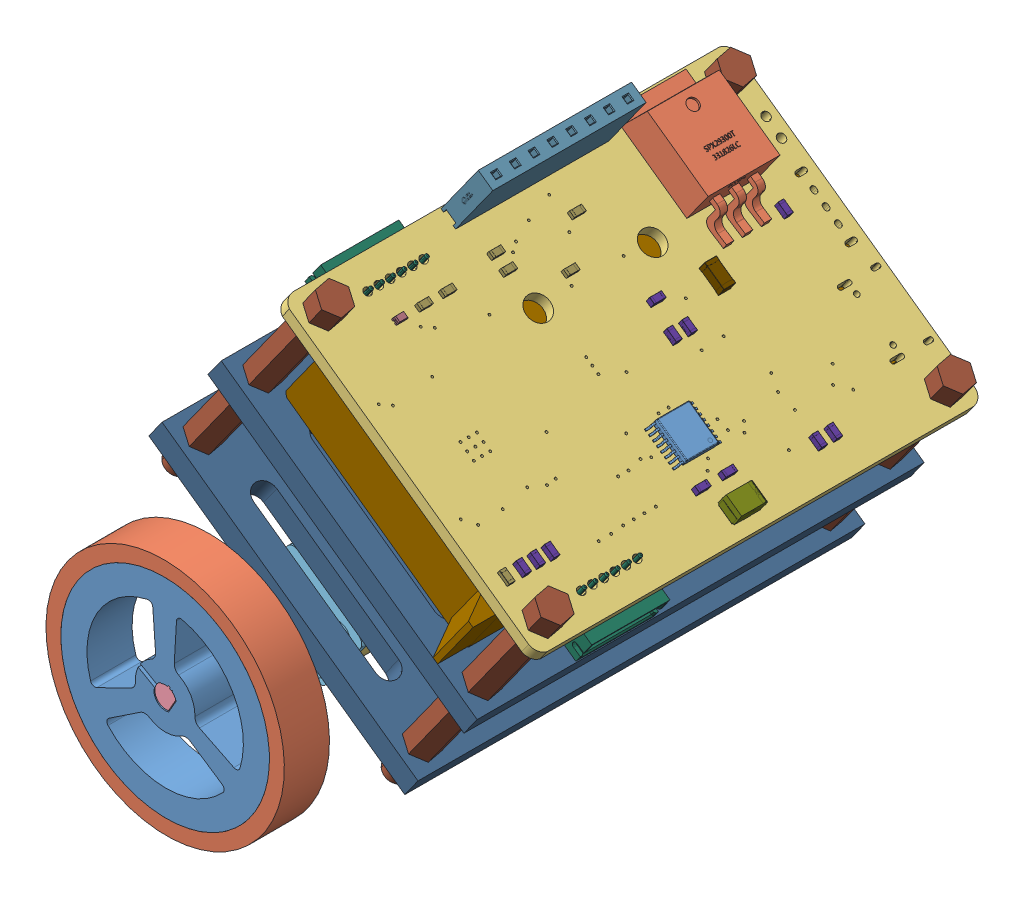
SolidWorks assembly 平衡车组装, configuration 默认. Lengths in mm.
Overall size (65.75 71.58 84.82).
118 component instances, 21 part files, 28 mates.
Components (placement in the parent):
- 轮胎-1: 轮胎 [默认] at (-1.4439 0.1126 20.4663) x (0.999988 -0.000017 0.004949) z (-0.004949 -0.006932 0.999964) size (28 28 6)
- 轮胎外胎-1: 轮胎外胎 [默认] at (-1.4439 0.1126 20.4663) x (0.781141 0.6243 0.008194) z (-0.004949 -0.006932 0.999964) size (32 32 6)
- n20 motor-2: n20 motor [轴长10mm] at (-1.1407 0.3816 3.3576) x (0.004949 0.006932 -0.999964) z (0.581014 0.813849 0.008518) size (36.2 12.14 10.87)
  - motor-1: motor [默认] at (-3.4114 0.0905 -5.0483) size (19.5 12 10)
  - n20_shaft-1: n20_shaft [10mm] at (-13.1114 0.0905 -0.0483) x (0 -0.096252 -0.995357) z (0 0.995357 -0.096252) size (3 12 3)
  - n20_gearbox-1: n20_gearbox [默认] at (-11.4114 0.0905 -0.0483) x (0 1 0) z (-1 0 0) size (12 10 9.7)
  - cross recessed countersunk head screws gb1-1: cross recessed countersunk head screws gb1 [GB_CROSS_SCREWS_TYPE4 M1.6X3-2  H type-N] at (-12.4614 -3.4095 2.4517) size (3 2.7 2.7)
  - cross recessed countersunk head screws gb1-2: cross recessed countersunk head screws gb1 [GB_CROSS_SCREWS_TYPE4 M1.6X3-2  H type-N] at (-12.4614 3.5905 -2.5483) x (1 0 0) z (0 0.116872 0.993147) size (3 2.7 2.7)
  - spur gear_gb-1: spur gear_gb [GB - Spur gear 0.25M 10T 20PA 2FW ---S10A75H50L1.0N] at (-8.4114 -2.9095 -2.5483) x (1 0 0) z (0 -0.845955 0.533254) size (2 2.87 3)
  - spur gear_gb-2: spur gear_gb [GB - Spur gear 0.25M 10T 20PA 2FW ---S10A75H50L1.0N] at (-4.4114 0.0905 -0.0483) x (-1 0 0) z (0 0.404067 -0.914729) size (2 2.87 3)
  - spur gear_gb-4: spur gear_gb [GB - Spur gear 0.25M 16T 20PA 2FW ---S16A75H50L1.0N] at (-6.4114 -2.9095 -2.5483) x (1 0 0) z (0 -0.712706 0.701463) size (2 4.44 4.44)
  - spur gear_gb-6: spur gear_gb [GB - Spur gear 0.25M 19T 20PA 2FW ---S19A75H50L1.0N] at (-9.9114 0.0905 -0.0483) x (1 0 0) z (0 0.321468 -0.94692) size (2 5.22 5.24)
  - spur gear_gb-8: spur gear_gb [GB - Spur gear 0.25M 11T 20PA 3FW ---S11A75H50L1.0N] at (-10.9114 3.0905 2.9517) x (1 0 0) z (0 -0.604063 0.796937) size (3 3.2 3.23)
  - spur gear_gb-10: spur gear_gb [GB - Spur gear 0.25M 19T 20PA 1FW ---S19A75H50L1.0N] at (-11.4114 0.0905 -0.0483) x (1 0 0) z (0 -0.330889 0.94367) size (1 5.22 5.24)
- 零件5-1: 零件5 [默认] at (-1.3018 0.3116 -8.2327) x (0.813878 -0.581035 0) z (0.004949 0.006932 -0.999964) size (11.6 18.42 6)
- 轮胎-2: 轮胎 [默认] at (-1.4735 0.071 -58.0123) x (0.999988 -0.000017 -0.004949) z (0.004949 0.006932 0.999964) size (28 28 6)
- 轮胎外胎-2: 轮胎外胎 [默认] at (-1.4735 0.071 -58.0123) x (0.781141 0.6243 -0.008194) z (0.004949 0.006932 0.999964) size (32 32 6)
- n20 motor-3: n20 motor [轴长10mm] at (-1.4302 -0.024 -34.8996) x (0.004949 0.006932 0.999964) z (-0.581014 -0.813849 0.008518) size (36.2 12.14 10.87)
  - motor-1: motor [默认] at (-3.4114 0.0905 -5.0483) size (19.5 12 10)
  - n20_shaft-1: n20_shaft [10mm] at (-13.1114 0.0905 -0.0483) x (0 -0.096252 -0.995357) z (0 0.995357 -0.096252) size (3 12 3)
  - n20_gearbox-1: n20_gearbox [默认] at (-11.4114 0.0905 -0.0483) x (0 1 0) z (-1 0 0) size (12 10 9.7)
  - cross recessed countersunk head screws gb1-1: cross recessed countersunk head screws gb1 [GB_CROSS_SCREWS_TYPE4 M1.6X3-2  H type-N] at (-12.4614 -3.4095 2.4517) size (3 2.7 2.7)
  - cross recessed countersunk head screws gb1-2: cross recessed countersunk head screws gb1 [GB_CROSS_SCREWS_TYPE4 M1.6X3-2  H type-N] at (-12.4614 3.5905 -2.5483) x (1 0 0) z (0 0.116872 0.993147) size (3 2.7 2.7)
  - spur gear_gb-1: spur gear_gb [GB - Spur gear 0.25M 10T 20PA 2FW ---S10A75H50L1.0N] at (-8.4114 -2.9095 -2.5483) x (1 0 0) z (0 -0.845955 0.533254) size (2 2.87 3)
  - spur gear_gb-2: spur gear_gb [GB - Spur gear 0.25M 10T 20PA 2FW ---S10A75H50L1.0N] at (-4.4114 0.0905 -0.0483) x (-1 0 0) z (0 0.404067 -0.914729) size (2 2.87 3)
  - spur gear_gb-4: spur gear_gb [GB - Spur gear 0.25M 16T 20PA 2FW ---S16A75H50L1.0N] at (-6.4114 -2.9095 -2.5483) x (1 0 0) z (0 -0.712706 0.701463) size (2 4.44 4.44)
  - spur gear_gb-6: spur gear_gb [GB - Spur gear 0.25M 19T 20PA 2FW ---S19A75H50L1.0N] at (-9.9114 0.0905 -0.0483) x (1 0 0) z (0 0.321468 -0.94692) size (2 5.22 5.24)
  - spur gear_gb-8: spur gear_gb [GB - Spur gear 0.25M 11T 20PA 3FW ---S11A75H50L1.0N] at (-10.9114 3.0905 2.9517) x (1 0 0) z (0 -0.604063 0.796937) size (3 3.2 3.23)
  - spur gear_gb-10: spur gear_gb [GB - Spur gear 0.25M 19T 20PA 1FW ---S19A75H50L1.0N] at (-11.4114 0.0905 -0.0483) x (1 0 0) z (0 -0.330889 0.94367) size (1 5.22 5.24)
- 零件5-2: 零件5 [默认] at (-1.3018 0.3116 -23.3136) x (-0.813878 0.581035 0) z (0.004949 0.006932 0.999964) size (11.6 18.42 6)
- 电池2S-1: 电池2S [默认] at (17.4767 27.9064 -17.9457) x (-0.004949 -0.006932 -0.999964) z (-0.581014 -0.813849 0.008518) size (62.44 30 12)
- 底板-1: 底板 [默认] at (1.0488 4.6094 -15.7714) x (-0.004949 -0.006932 -0.999964) z (0.581014 0.813849 -0.008518) size (60 42 3)
- 底板-2: 底板 [默认] at (8.9065 15.6161 -15.818) x (-0.004949 -0.006932 -0.999964) z (0.581014 0.813849 -0.008518) size (60 42 3)
- 铜柱-1: 铜柱 [默认] at (-11.9913 17.3229 -42.7274) x (0.665274 -0.468864 0.581014) z (-0.581014 -0.813849 0.008518) size (4.05 4.02 36)
- 铜柱-2: 铜柱 [默认] at (-11.7244 17.6968 11.2021) x (0.665274 -0.468864 0.581014) z (-0.581014 -0.813849 0.008518) size (4.05 4.02 36)
- 铜柱-3: 铜柱 [默认] at (17.308 -3.5948 -42.796) x (0.665274 -0.468864 0.581014) z (-0.581014 -0.813849 0.008518) size (4.05 4.02 36)
- 铜柱-4: 铜柱 [默认] at (17.5753 -3.2205 11.2021) x (0.665274 -0.468864 0.581014) z (-0.581014 -0.813849 0.008518) size (4.05 4.02 36)
- 3D_PCB-1: 3D_PCB [默认] at (34.8613 15.8296 13.9846) x (-0.004949 -0.006932 -0.999964) z (0.581014 0.813849 -0.008518) size (59.92 44.49 13.72)
  - 3D_PCB.step-1: 3D_PCB.step [默认] at origin size (59.92 44.49 13.72)
    - R1.step-1: R1.step [默认] at (33.7821 35.0521 1.6001) x (-1 0 0) z (0 0 1) size (1.6 0.8 0.51)
      - R0603.step-1: R0603.step [默认] at origin size (1.6 0.8 0.51)
        - COMPOUND.step-1: COMPOUND.step [默认] at origin size (1.6 0.8 0.51)
    - R2.step-1: R2.step [默认] at (29.2101 30.4801 1.6001) size (1.6 0.8 0.51)
      - R0603.step-1: R0603.step [默认] at origin size (1.6 0.8 0.51)
        - COMPOUND.step-1: COMPOUND.step [默认] at origin size (1.6 0.8 0.51)
    - R3.step-1: R3.step [默认] at (23.3409 33.5471 1.6001) size (1.6 0.8 0.51)
      - R0603.step-1: R0603.step [默认] at origin size (1.6 0.8 0.51)
        - COMPOUND.step-1: COMPOUND.step [默认] at origin size (1.6 0.8 0.51)
    - R4.step-1: R4.step [默认] at (23.3409 35.5248 1.6001) size (1.6 0.8 0.51)
      - R0603.step-1: R0603.step [默认] at origin size (1.6 0.8 0.51)
        - COMPOUND.step-1: COMPOUND.step [默认] at origin size (1.6 0.8 0.51)
    - R5.step-1: R5.step [默认] at (12.954 34.6711 1.6001) size (1.6 0.8 0.51)
      - R0603.step-1: R0603.step [默认] at origin size (1.6 0.8 0.51)
        - COMPOUND.step-1: COMPOUND.step [默认] at origin size (1.6 0.8 0.51)
    - R6.step-1: R6.step [默认] at (2.286 8.128 1.6001) x (0 1 0) z (0 0 1) size (1.6 0.8 0.51)
      - R0603.step-1: R0603.step [默认] at origin size (1.6 0.8 0.51)
        - COMPOUND.step-1: COMPOUND.step [默认] at origin size (1.6 0.8 0.51)
    - R7.step-1: R7.step [默认] at (16.129 34.6711 1.6001) x (-1 0 0) z (0 0 1) size (1.6 0.8 0.51)
      - R0603.step-1: R0603.step [默认] at origin size (1.6 0.8 0.51)
        - COMPOUND.step-1: COMPOUND.step [默认] at origin size (1.6 0.8 0.51)
    - LED1.step-1: LED1.step [默认] at (9.779 34.6711 1.6001) size (1.49 0.75 0.56)
      - LED0603-RD_BLUE.step-1: LED0603-RD_BLUE.step [默认] at origin size (1.49 0.75 0.56)
        - COMPOUND-0.step-1: COMPOUND-0.step [默认] at origin size (1.49 0.75 0.56)
    - U6.step-1: U6.step [默认] at (40.3861 40.6401 1.6001) x (0 -1 0) z (0 0 1) size (2.38 20.58 11.62)
      - MPU6050.step-1: MPU6050.step [默认] at origin size (2.38 20.58 11.62)
        - SOLID.step-1: SOLID.step [默认] at origin size (2.38 20.58 11.62)
    - CN1.step-1: CN1.step [默认] at (12.4 3.429 0) x (-1 0 0) z (0 0 -1) size (10.5 4.99 6.1)
      - CONN-TH_ZH1.5-6AW.step-1: CONN-TH_ZH1.5-6AW.step [默认] at origin size (10.5 4.99 6.1)
        - SOLID-1.step-1: SOLID-1.step [默认] at origin size (10.5 4.99 6.1)
    - CN2.step-1: CN2.step [默认] at (12.4 38.4811 0) x (1 0 0) z (0 0 -1) size (10.5 4.99 6.1)
      - CONN-TH_ZH1.5-6AW.step-1: CONN-TH_ZH1.5-6AW.step [默认] at origin size (10.5 4.99 6.1)
        - SOLID-1.step-1: SOLID-1.step [默认] at origin size (10.5 4.99 6.1)
    - U4.step-1: U4.step [默认] at (29.3332 2.8925 1.6001) x (-1 0 0) z (0 0 1) size (3.7 2.6 2)
      - CAP-SMD_L3.5-W2.8-FD.step-1: CAP-SMD_L3.5-W2.8-FD.step [默认] at origin size (3.7 2.6 2)
        - COMPOUND-2.step-1: COMPOUND-2.step [默认] at origin size (3.7 2.6 2)
    - C1.step-1: C1.step [默认] at (41.0883 4.4926 1.6001) x (0 -1 0) z (0 0 1) size (1.6 0.8 0.8)
      - C0603.step-1: C0603.step [默认] at origin size (1.6 0.8 0.8)
        - =_[0_1_1_27].step-1: =_[0_1_1_27].step [默认] at (0 0 0.4) size (1.6 0.8 0.8)
    - C2.step-1: C2.step [默认] at (43.1203 4.4926 1.6001) x (0 -1 0) z (0 0 1) size (1.6 0.8 0.8)
      - C0603.step-1: C0603.step [默认] at origin size (1.6 0.8 0.8)
        - =_[0_1_1_27].step-1: =_[0_1_1_27].step [默认] at (0 0 0.4) size (1.6 0.8 0.8)
    - C3.step-1: C3.step [默认] at (53.5887 25.3846 1.6001) x (0 -1 0) z (0 0 1) size (1.6 0.8 0.8)
      - C0603.step-1: C0603.step [默认] at origin size (1.6 0.8 0.8)
        - =_[0_1_1_27].step-1: =_[0_1_1_27].step [默认] at (0 0 0.4) size (1.6 0.8 0.8)
    - C5.step-1: C5.step [默认] at (34.4275 20.1981 1.6001) x (0 1 0) z (0 0 1) size (1.6 0.8 0.8)
      - C0603.step-1: C0603.step [默认] at origin size (1.6 0.8 0.8)
        - =_[0_1_1_27].step-1: =_[0_1_1_27].step [默认] at (0 0 0.4) size (1.6 0.8 0.8)
    - C6.step-1: C6.step [默认] at (36.4595 20.1981 1.6001) x (0 1 0) z (0 0 1) size (1.6 0.8 0.8)
      - C0603.step-1: C0603.step [默认] at origin size (1.6 0.8 0.8)
        - =_[0_1_1_27].step-1: =_[0_1_1_27].step [默认] at (0 0 0.4) size (1.6 0.8 0.8)
    - C7.step-1: C7.step [默认] at (35.3061 24.003 1.6001) x (-1 0 0) z (0 0 1) size (1.6 0.8 0.8)
      - C0603.step-1: C0603.step [默认] at origin size (1.6 0.8 0.8)
        - =_[0_1_1_27].step-1: =_[0_1_1_27].step [默认] at (0 0 0.4) size (1.6 0.8 0.8)
    - C8.step-1: C8.step [默认] at (8.1226 8.1125 1.6001) x (0 -1 0) z (0 0 1) size (1.6 0.8 0.8)
      - C0603.step-1: C0603.step [默认] at origin size (1.6 0.8 0.8)
        - =_[0_1_1_27].step-1: =_[0_1_1_27].step [默认] at (0 0 0.4) size (1.6 0.8 0.8)
    - C10.step-1: C10.step [默认] at (4.3126 8.1125 1.6001) x (0 -1 0) z (0 0 1) size (1.6 0.8 0.8)
      - C0603.step-1: C0603.step [默认] at origin size (1.6 0.8 0.8)
        - =_[0_1_1_27].step-1: =_[0_1_1_27].step [默认] at (0 0 0.4) size (1.6 0.8 0.8)
    - C9.step-1: C9.step [默认] at (6.223 8.128 1.6001) x (0 -1 0) z (0 0 1) size (1.6 0.8 0.8)
      - C0603.step-1: C0603.step [默认] at origin size (1.6 0.8 0.8)
        - =_[0_1_1_27].step-1: =_[0_1_1_27].step [默认] at (0 0 0.4) size (1.6 0.8 0.8)
    - C12.step-1: C12.step [默认] at (30.3492 6.1945 1.6001) size (1.6 0.8 0.8)
      - C0603.step-1: C0603.step [默认] at origin size (1.6 0.8 0.8)
        - =_[0_1_1_27].step-1: =_[0_1_1_27].step [默认] at (0 0 0.4) size (1.6 0.8 0.8)
    - C11.step-1: C11.step [默认] at (26.7932 6.1945 1.6001) size (1.6 0.8 0.8)
      - C0603.step-1: C0603.step [默认] at origin size (1.6 0.8 0.8)
        - =_[0_1_1_27].step-1: =_[0_1_1_27].step [默认] at (0 0 0.4) size (1.6 0.8 0.8)
    - C4.step-1: C4.step [默认] at (42.5451 22.987 1.6001) x (0 -1 0) z (0 0 1) size (3.2 1.6 1.3)
      - C1206.step-1: C1206.step [默认] at origin size (3.2 1.6 1.3)
        - =_[0_1_1_41].step-1: =_[0_1_1_41].step [默认] at (0 0 0.65) size (3.2 1.6 1.3)
    - U8.step-1: U8.step [默认] at (28.8291 11.43 1.6001) x (0 1 0) z (0 0 1) size (5 6.4 1.2)
      - ETSSOP-16_L5.0-W4.4-P0.65-LS6.4-BL-EP.step-1: ETSSOP-16_L5.0-W4.4-P0.65-LS6.4-BL-EP.step [默认] at origin size (5 6.4 1.2)
        - SOLID-3.step-1: SOLID-3.step [默认] at origin size (5 6.4 1.2)
    - U7.step-1: U7.step [默认] at (48.3871 31.3208 1.6001) x (0 1 0) z (0 0 1) size (16.52 9.65 5.42)
      - TO-263-3_L8.6-W10.2-P2.54-LS14.4-TL.step-1: TO-263-3_L8.6-W10.2-P2.54-LS14.4-TL.step [默认] at origin size (16.52 9.65 5.42)
        - COMPOUND-4.step-1: COMPOUND-4.step [默认] at origin size (16.52 9.65 5.42)
    - COMPOUND-5.step-1: COMPOUND-5.step [默认] at origin size (59.92 42.01 1.6)
Mates (geometry in assembly coordinates):
- 重合3: coincident aligned: circle of 轮胎-1; circle of 轮胎外胎-1
- 同心1: concentric aligned: circle of n20 motor-2/motor-1; circle of 零件5-1
- 重合5: coincident anti-aligned: plane of n20 motor-2/motor-1 through (6.6033 1.0582 -8.1884) normal (0.004949 0.006932 -0.999964); plane of 零件5-1 through (-0.3069 -2.2102 -8.2452) normal (-0.004949 -0.006932 0.999964)
- 平行3: parallel anti-aligned: line of n20 motor-2/motor-1 through (-1.7413 6.8627 6.4111) axis (0.813878 -0.581035 0); line of 零件5-1 through (8.0549 3.8243 -13.1622) axis (-0.813878 0.581035 0)
- 同心2: concentric aligned: circle of 轮胎-1; circle of 零件5-1
- 平行5: parallel anti-aligned: line of 轮胎-1 through (-0.9756 -1.3124 20.4587) axis (0.499979 0.865996 0.008478); line of n20 motor-2/n20_shaft-1 through (0.0683 0.7029 26.4781) axis (-0.499979 -0.865996 -0.008478)
- 重合10: coincident aligned: plane of 轮胎-1 through (-1.4735 0.071 26.4661) normal (-0.004949 -0.006932 0.999964); plane of n20 motor-2/n20_shaft-1 through (-1.3567 0.2347 26.4678) normal (-0.004949 -0.006932 0.999964)
- 平行6: parallel aligned: plane of 零件5-2 through (11.0584 8.0314 -18.4281) normal (0.581014 0.813849 -0.008518); plane of 电池2S-1 through (17.4767 27.9064 -17.9457) normal (0.581014 0.813849 -0.008518)
- 平行7: parallel aligned: plane of 零件5-2 through (-1.0185 10.3019 -18.3841) normal (-0.813878 0.581035 0); plane of 电池2S-1 through (-1.5601 27.0567 11.1555) normal (-0.813878 0.581035 0)
- 平行8: parallel anti-aligned: plane of 零件5-2 through (11.0584 8.0314 -18.4281) normal (0.581014 0.813849 -0.008518); plane of 底板-1 through (1.0488 4.6094 -15.7714) normal (-0.581014 -0.813849 0.008518)
- 平行12: parallel anti-aligned: plane of 电池2S-1 through (17.4767 27.9064 -17.9457) normal (0.581014 0.813849 -0.008518); plane of 底板-2 through (8.9065 15.6161 -15.818) normal (-0.581014 -0.813849 0.008518)
- 平行13: parallel aligned: plane of 电池2S-1 through (22.8563 9.6257 11.1555) normal (0.813878 -0.581035 0); plane of 底板-2 through (27.8895 6.0638 14.1553) normal (0.813878 -0.581035 0)
- 重合21: coincident anti-aligned: plane of 电池2S-1 through (10.5046 18.1402 -17.8435) normal (-0.581014 -0.813849 0.008518); plane of 底板-2 through (10.6496 18.0576 -15.8436) normal (0.581014 0.813849 -0.008518)
- 重合22: coincident anti-aligned: plane of 底板-1 through (2.7918 7.051 -15.797) normal (0.581014 0.813849 -0.008518); plane of 铜柱-1 through (-11.9913 17.3229 -42.7274) normal (-0.581014 -0.813849 0.008518)
- 同心4: concentric anti-aligned: circle of 底板-2; circle of 铜柱-1
- 同心6: concentric anti-aligned: circle of 底板-1; circle of 铜柱-2
- 重合23: coincident anti-aligned: plane of 底板-1 through (2.7918 7.051 -15.797) normal (0.581014 0.813849 -0.008518); plane of 铜柱-2 through (-11.7244 17.6968 11.2021) normal (-0.581014 -0.813849 0.008518)
- 同心7: concentric anti-aligned: circle of 底板-1; circle of 铜柱-3
- 重合25: coincident anti-aligned: plane of 底板-1 through (2.7918 7.051 -15.797) normal (0.581014 0.813849 -0.008518); plane of 铜柱-3 through (17.308 -3.5948 -42.796) normal (-0.581014 -0.813849 0.008518)
- 重合26: coincident anti-aligned: plane of 底板-1 through (2.7918 7.051 -15.797) normal (0.581014 0.813849 -0.008518); plane of 铜柱-4 through (17.5753 -3.2205 11.2021) normal (-0.581014 -0.813849 0.008518)
- 同心8: concentric anti-aligned: circle of 底板-1; circle of 铜柱-4
- 平行14: parallel anti-aligned: plane of 电池2S-1 through (17.4767 27.9064 -17.9457) normal (0.581014 0.813849 -0.008518); plane of 3D_PCB-1/3D_PCB.step-1/COMPOUND-5.step-1 through (17.6074 27.8335 -15.9921) normal (-0.581014 -0.813849 0.008518)
- 平行15: parallel anti-aligned: line of 电池2S-1 through (28.6027 20.2565 10.0533) axis (-0.004949 -0.006932 -0.999964); line of 3D_PCB-1/3D_PCB.step-1/COMPOUND-5.step-1 through (35.4908 16.7332 -44.59) axis (0.004949 0.006932 0.999964)
- 同心9: concentric anti-aligned: circle of 铜柱-3; circle of 3D_PCB-1/3D_PCB.step-1/COMPOUND-5.step-1
- 重合28: coincident anti-aligned: line of n20 motor-3/n20_gearbox-1 through (5.4768 1.2014 -39.3539) axis (-0.813878 0.581035 0); line of 底板-1 through (-7.2067 10.2563 -39.3539) axis (0.813878 -0.581035 0)
- 重合29: coincident anti-aligned: line of n20 motor-2/n20_gearbox-1 through (-2.4285 7.3387 7.8111) axis (0.813878 -0.581035 0); line of 底板-1 through (9.3043 -1.0374 7.8111) axis (-0.813878 0.581035 0)
- 重合30: coincident anti-aligned: line of 电池2S-1 through (-0.6214 25.79 -45.8425) axis (0.813878 -0.581035 0); line of 底板-2 through (27.5925 5.6479 -45.8425) axis (-0.813878 0.581035 0)
- 重合32: coincident anti-aligned: line of 电池2S-1 through (28.3255 19.8683 -45.9447) axis (-0.813878 0.581035 0); line of 3D_PCB-1/3D_PCB.step-1/COMPOUND-5.step-1 through (1.3857 39.1009 -45.9447) axis (0.813878 -0.581035 0)
